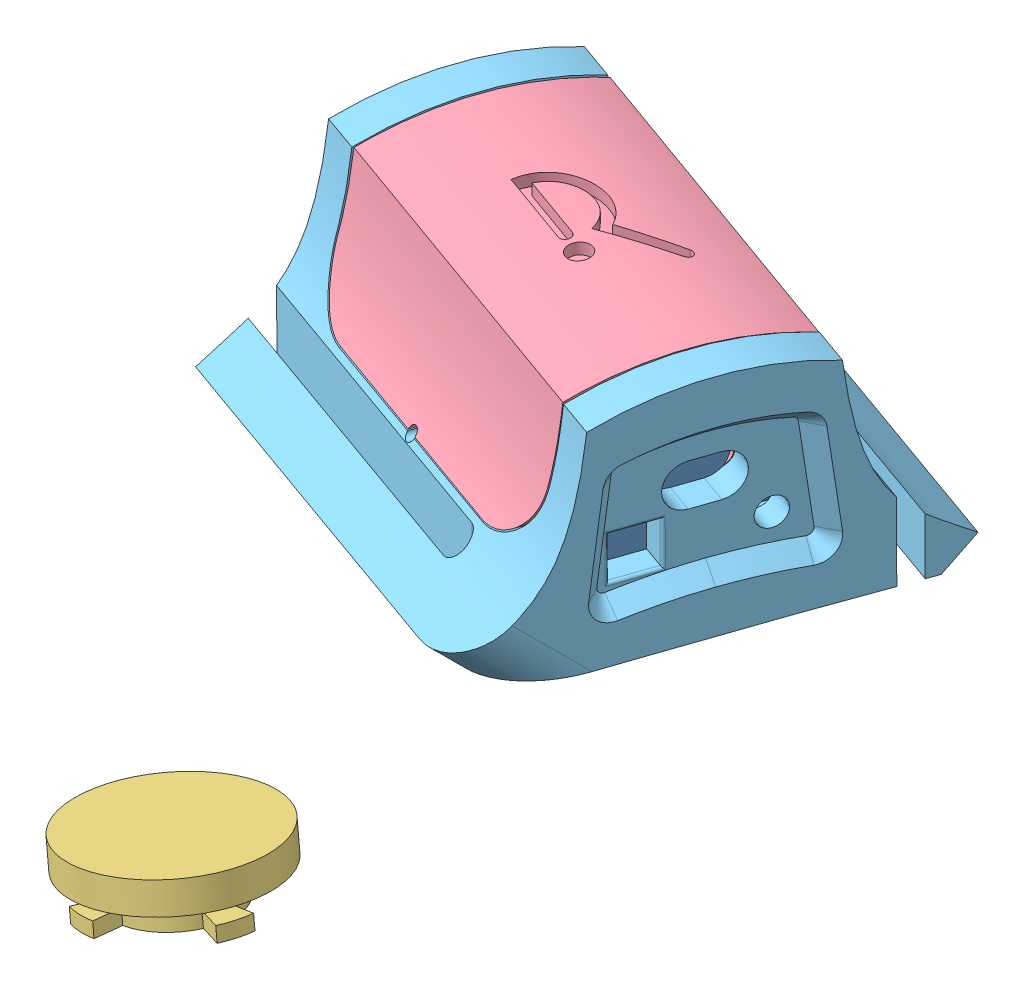
SolidWorks assembly NatesAssebly, configuration Default. Lengths in mm.
Overall size (97.72 77.99 138.12).
5 component instances, 5 part files, 0 mates.
Components (placement in the parent):
- BoardIMU-1: BoardIMU [Default] at (-16.9245 48.7612 57.3983) x (-0.941649 0 -0.336597) z (0.336597 0 -0.941649) size (55.5 26 29)
- Battery-1: Battery [Default] at (-14.1837 68.7612 58.6435) x (-0.941649 0 -0.336597) z (0.336597 0 -0.941649) size (53.5 7 30)
- Base-2: Base [Default] at (10.0725 10.2731 122.6482) x (-0.926452 -0.13653 0.35078) z (-0.172349 0.982339 -0.072849) size (32 32 10.5)
- CaseLid-1: CaseLid [Default] at (14.2523 47.6118 53.365) x (0.336597 0 -0.941649) z (0.941649 0 0.336597) size (50.53 25.78 63.27)
- CaseMain-1: CaseMain [Default] at (14.221 47.7617 53.2836) x (0.333036 0.007008 -0.942888) z (0.942914 -0.003653 0.333017) size (74.93 40.82 77.12)
